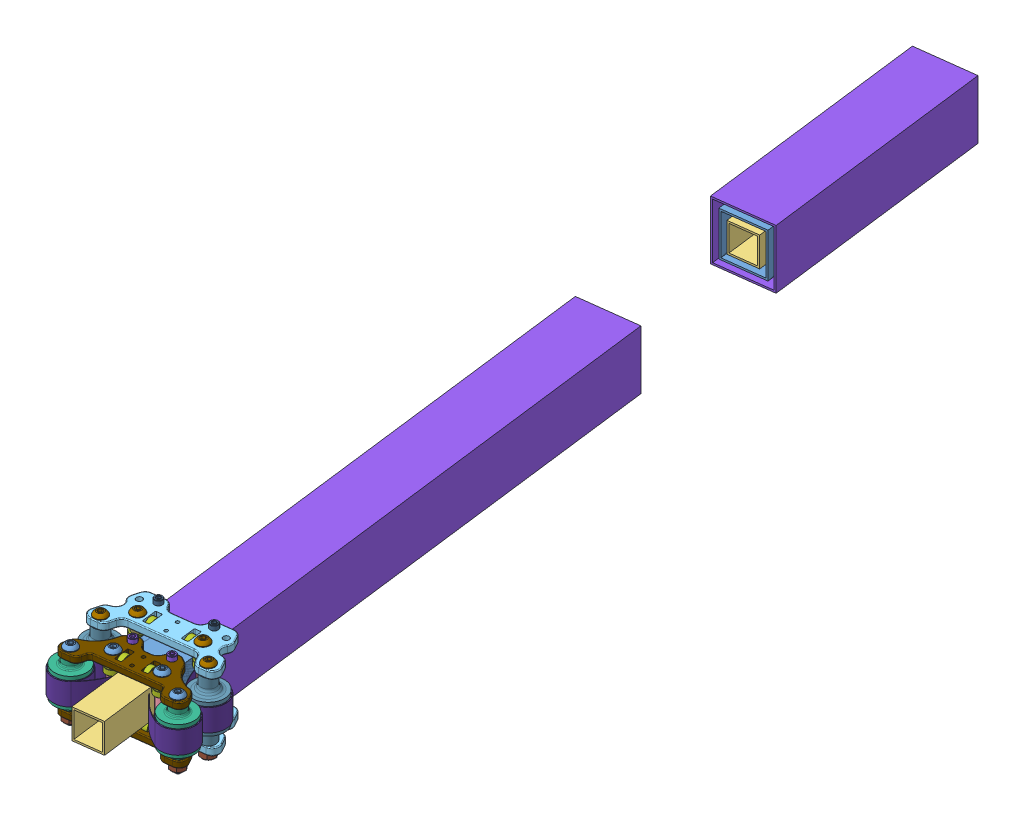
SolidWorks assembly telescoping arm, configuration Default. Lengths in mm.
Overall size (219.65 74.15 857.68).
95 component instances, 28 part files, 0 mates.
Components (placement in the parent):
- 2 x 2 Inch Stage.stp-1: 2 x 2 Inch Stage.stp [Default] at (1113.4745 353.0023 985.2524) size (183.93 74.15 806.3)
  - 1.5_inch_stage.stp-1: 1.5_inch_stage.stp [Default] at (-107.3783 0 -858.4701) size (133.34 47.37 731.79)
    - 1.5x1.5 bar.stp-1: 1.5x1.5 bar.stp [Default] at (575.8182 404.7167 1377.5179) x (-0.992268 0 0.124114) z (-0.124114 0 -0.992268) size (38.1 38.1 711.2)
    - 2x2StageInternalEndBlock.stp-1: 2x2StageInternalEndBlock.stp [Default] at (413.7616 573.8056 681.0462) x (-0.992268 0 0.124114) z (-0.124114 0 -0.992268) size (47.37 47.37 40.64)
    - 94615A115_Brass Flanged Screw-to-Expand Inserts (1).stp-1: 94615A115_Brass Flanged Screw-to-Expand Inserts (1).stp [Default] at (431.7042 573.8056 688.4011) x (0.114575 0.384452 0.916007) z (-0.047716 0.923145 -0.381479) size (7.92 9.53 7.92)
    - 97763A231_18-8 Stainless Steel Button Head Hex Drive Screws.stp-1: 97763A231_18-8 Stainless Steel Button Head Hex Drive Screws.stp [Default] at (398.9269 573.8691 692.501) x (0.124114 0.000773 0.992268) z (-0.992268 0 0.124114) size (9.17 9.17 12.09)
  - 2x2ClimberPlateAssemblyNew.stp-1: 2x2ClimberPlateAssemblyNew.stp [Default] at (310.1471 56.4224 225.65) x (0.992268 0 -0.124114) z (0.124114 0 0.992268) size (102.18 13.04 44.45)
    - 2x2NewClimberPlateConcept.stp-1: 2x2NewClimberPlateConcept.stp [Default] at (71.6924 542.7705 -285.0056) x (-1 0 0) z (0 1 0) size (102.18 44.45 8.76)
    - 98381A545_ALLOY STEEL DOWEL PIN.stp-1: 98381A545_ALLOY STEEL DOWEL PIN.stp [Default] at (46.4194 542.6435 281.8589) x (-1 0 0) z (0 -0.467381 0.884056) size (34.92 6.35 6.35)
    - TTB-0027_.50OD_.25ID_.188WD.stp-1: TTB-0027_.50OD_.25ID_.188WD.stp [Default] at (31.3382 542.6435 281.8589) x (0 0.013886 0.999904) z (-1 0 0) size (12.7 12.7 4.76)
    - TTB-0027_.50OD_.25ID_.188WD.stp-2: TTB-0027_.50OD_.25ID_.188WD.stp [Default] at (61.5007 542.6435 281.8589) x (0 0.005291 0.999986) z (-1 0 0) size (12.7 12.7 4.76)
  - 2x2ClimberPlateAssemblyNew.stp-2: 2x2ClimberPlateAssemblyNew.stp [Default] at (402.0161 1091.1635 214.1589) x (-0.992268 0 0.124114) z (0.124114 0 0.992268) size (102.18 13.04 44.45)
    - 2x2NewClimberPlateConcept.stp-1: 2x2NewClimberPlateConcept.stp [Default] at (71.6924 542.7705 -285.0056) x (-1 0 0) z (0 1 0) size (102.18 44.45 8.76)
    - 98381A545_ALLOY STEEL DOWEL PIN.stp-1: 98381A545_ALLOY STEEL DOWEL PIN.stp [Default] at (46.4194 542.6435 281.8589) x (-1 0 0) z (0 -0.467381 0.884056) size (34.92 6.35 6.35)
    - TTB-0027_.50OD_.25ID_.188WD.stp-1: TTB-0027_.50OD_.25ID_.188WD.stp [Default] at (31.3382 542.6435 281.8589) x (0 0.013886 0.999904) z (-1 0 0) size (12.7 12.7 4.76)
    - TTB-0027_.50OD_.25ID_.188WD.stp-2: TTB-0027_.50OD_.25ID_.188WD.stp [Default] at (61.5007 542.6435 281.8589) x (0 0.005291 0.999986) z (-1 0 0) size (12.7 12.7 4.76)
  - 2x2 Box.stp-1: 2x2 Box.stp [Default] at (320.6921 548.3929 -267.6788) x (-0.992268 0 0.124114) z (0.124114 0 0.992268) size (50.8 50.8 762)
  - 91255A529_NO THREADS_Button Head Hex Drive Screw (1).stp-1: 91255A529_NO THREADS_Button Head Hex Drive Screw (1).stp [Default] at (366.1553 609.0227 504.1716) x (0.396837 0 -0.917889) z (0 1 0) size (11.1 11.1 73.2)
  - 90044A515_Black-Oxide Alloy Steel Socket Head Screw.stp-1: 90044A515_Black-Oxide Alloy Steel Socket Head Screw.stp [Default] at (410.673 605.6699 482.6046) x (0.993633 0 -0.112668) z (0 1 0) size (6.86 6.86 74.15)
  - 90044A515_Black-Oxide Alloy Steel Socket Head Screw.stp-2: 90044A515_Black-Oxide Alloy Steel Socket Head Screw.stp [Default] at (367.8773 605.6699 487.9575) x (0.430705 0 0.902493) z (0 1 0) size (6.86 6.86 74.15)
  - 91255A529_NO THREADS_Button Head Hex Drive Screw (1).stp-2: 91255A529_NO THREADS_Button Head Hex Drive Screw (1).stp [Default] at (351.7432 609.0227 521.973) x (-0.099638 0 0.995024) z (0 1 0) size (11.1 11.1 73.2)
  - 91255A529_NO THREADS_Button Head Hex Drive Screw (1).stp-3: 91255A529_NO THREADS_Button Head Hex Drive Screw (1).stp [Default] at (434.6883 609.0227 511.5981) x (1 0 0) z (0 1 0) size (11.1 11.1 73.2)
  - 91255A529_NO THREADS_Button Head Hex Drive Screw (1).stp-4: 91255A529_NO THREADS_Button Head Hex Drive Screw (1).stp [Default] at (416.3356 609.0227 497.895) x (0.998718 0 -0.050617) z (0 1 0) size (11.1 11.1 73.2)
  - TTB-0027_.50OD_.25ID_.188WD.stp-1: TTB-0027_.50OD_.25ID_.188WD.stp [Default] at (416.3356 557.2004 497.895) x (-0.032207 0 0.999481) z (0 1 0) size (12.7 12.7 4.76)
  - TTB-0027_.50OD_.25ID_.188WD.stp-2: TTB-0027_.50OD_.25ID_.188WD.stp [Default] at (416.3356 590.4617 497.895) x (-0.065423 0 0.997858) z (0 1 0) size (12.7 12.7 4.76)
  - TTB-0027_.50OD_.25ID_.188WD.stp-3: TTB-0027_.50OD_.25ID_.188WD.stp [Default] at (366.1553 557.2004 504.1716) x (-0.065423 0 0.997858) z (0 1 0) size (12.7 12.7 4.76)
  - TTB-0027_.50OD_.25ID_.188WD.stp-4: TTB-0027_.50OD_.25ID_.188WD.stp [Default] at (366.1553 590.4617 504.1716) x (-0.065423 0 0.997858) z (0 1 0) size (12.7 12.7 4.76)
  - 90101A230_18-8 Stainless Steel Thin Nylon-Insert Locknut.stp-1: 90101A230_18-8 Stainless Steel Thin Nylon-Insert Locknut.stp [Default] at (434.6883 541.9159 511.5981) x (0.797272 0 -0.60362) z (-0.60362 0 -0.797272) size (11.11 5.2 12.83)
  - 90101A230_18-8 Stainless Steel Thin Nylon-Insert Locknut.stp-2: 90101A230_18-8 Stainless Steel Thin Nylon-Insert Locknut.stp [Default] at (416.3356 541.9159 497.895) x (0.921386 0 0.388648) z (0.388648 0 -0.921386) size (11.11 5.2 12.83)
  - 90101A230_18-8 Stainless Steel Thin Nylon-Insert Locknut.stp-3: 90101A230_18-8 Stainless Steel Thin Nylon-Insert Locknut.stp [Default] at (351.7432 541.9159 521.973) x (0.797272 0 -0.60362) z (-0.60362 0 -0.797272) size (11.11 5.2 12.83)
  - 90101A230_18-8 Stainless Steel Thin Nylon-Insert Locknut.stp-4: 90101A230_18-8 Stainless Steel Thin Nylon-Insert Locknut.stp [Default] at (366.1553 541.9159 504.1716) x (0.797272 0 -0.60362) z (-0.60362 0 -0.797272) size (11.11 5.2 12.83)
  - QuaterInchTelescopingSpacer.stp-1: QuaterInchTelescopingSpacer.stp [Default] at (391.2422 599.1929 504.1716) x (1 0 0) z (0 -1 0) size (9.27 9.27 6.35)
  - QuaterInchTelescopingSpacer.stp-2: QuaterInchTelescopingSpacer.stp [Default] at (391.2422 554.8191 504.1844) x (1 0 0.000511) z (0 -1 0) size (9.27 9.27 6.35)
  - 1.122InchTelescopingSpacer.stp-1: 1.122InchTelescopingSpacer.stp [Default] at (391.2422 588.0804 504.1716) x (1 0 0) z (0 -1 0) size (8.76 8.76 28.5)
  - QuaterInchTelescopingSpacer.stp-3: QuaterInchTelescopingSpacer.stp [Default] at (440.4399 599.1929 504.8475) x (0.96083 0 0.277139) z (0 -1 0) size (9.27 9.27 6.35)
  - QuaterInchTelescopingSpacer.stp-4: QuaterInchTelescopingSpacer.stp [Default] at (409.5553 554.8191 522.0482) x (-0.270275 0 0.962783) z (0 -1 0) size (9.27 9.27 6.35)
  - 94615A115_Brass Flanged Screw-to-Expand Inserts (1).stp-1: 94615A115_Brass Flanged Screw-to-Expand Inserts (1).stp [Default] at (290.8052 573.8056 -165.8762) x (0.123955 0.050546 0.991) z (0.006274 -0.998722 0.050156) size (7.92 9.53 7.92)
  - 97763A231_18-8 Stainless Steel Button Head Hex Drive Screws.stp-1: 97763A231_18-8 Stainless Steel Button Head Hex Drive Screws.stp [Default] at (323.7085 573.8691 -169.9917) x (-0.124114 0 -0.992268) z (0.992268 0 -0.124114) size (9.17 9.17 12.09)
  - 1.122InchTelescopingSpacer.stp-2: 1.122InchTelescopingSpacer.stp [Default] at (441.4226 588.0804 497.895) x (1 0 0) z (0 -1 0) size (8.76 8.76 28.5)
  - 1InchCFSpringRetentionSpacer_BaseStage.stp-1: 1InchCFSpringRetentionSpacer_BaseStage.stp [Default] at (351.7432 564.2679 521.973) x (1 0 0) z (0 -1 0) size (27.94 27.94 15.88)
  - 1InchCFSpringRetentionSpacer_BaseStage.stp-2: 1InchCFSpringRetentionSpacer_BaseStage.stp [Default] at (434.6883 583.3179 511.5981) x (-0.043542 0 0.999052) z (0 1 0) size (27.94 27.94 15.88)
  - 1InchCFSpringRetentionSpacer_BaseStage.stp-3: 1InchCFSpringRetentionSpacer_BaseStage.stp [Default] at (351.7432 583.3179 521.973) x (1 0 0) z (0 1 0) size (27.94 27.94 15.88)
  - 1InchCFSpringRetentionSpacer_BaseStage.stp-4: 1InchCFSpringRetentionSpacer_BaseStage.stp [Default] at (434.6883 564.2679 511.5981) x (0.999991 0 -0.00417) z (0 -1 0) size (27.94 27.94 15.88)
  - 90101A009_18-8 Stainless Steel Thin Nylon-Insert Locknut (1).stp-1: 90101A009_18-8 Stainless Steel Thin Nylon-Insert Locknut (1).stp [Default] at (368.252 541.9159 487.9106) x (0.797272 0 -0.60362) z (-0.60362 0 -0.797272) size (8.73 4.37 10.08)
  - 9293K56_SpringRoller.stp-1: 9293K56_SpringRoller.stp [Default] at (351.7432 564.2679 521.973) x (0.41705 0 -0.908884) z (0 1 0) size (20.07 20.07 19.05)
  - 9293K56_SpringRoller.stp-2: 9293K56_SpringRoller.stp [Default] at (434.6883 583.3179 511.5981) x (0.41705 0 0.908884) z (0 -1 0) size (20.07 20.07 19.05)
  - 9293K56_Constant-Force Spring.stp-1: 9293K56_Constant-Force Spring.stp [Default] at (434.7326 573.7929 511.5599) x (0 -1 0) z (-0.934501 0 0.355959) size (19.06 41.04 33.21)
  - 9293K56_Constant-Force Spring.stp-2: 9293K56_Constant-Force Spring.stp [Default] at (351.6902 573.7929 521.9484) x (0 1 0) z (0.996341 0 0.085466) size (19.06 41.04 33.21)
  - 90101A009_18-8 Stainless Steel Thin Nylon-Insert Locknut (1).stp-2: 90101A009_18-8 Stainless Steel Thin Nylon-Insert Locknut (1).stp [Default] at (410.673 541.9159 482.6046) x (0.797272 0 -0.60362) z (-0.60362 0 -0.797272) size (8.73 4.37 10.08)
- Stage 2 BOM - 1.5 inch to 1 inch Kit.stp-1: Stage 2 BOM - 1.5 inch to 1 inch Kit.stp [Default] at (1071.3002 772.575 539.439) x (0.992268 0 -0.124114) z (0.124114 0 0.992268) size (125.22 66.32 768.66)
  - 1.5ClimberPlateNewDesign.stp-1: 1.5ClimberPlateNewDesign.stp [Default] at (293.5653 129.5314 1017.7273) x (1 0 0) z (0 1 0) size (98.65 41.27 8)
  - 1.5ClimberPlateNewDesign.stp-2: 1.5ClimberPlateNewDesign.stp [Default] at (331.6653 179.0614 1017.7273) x (-1 0 0) z (0 -1 0) size (98.65 41.27 8)
  - 91255A528_NO THREADS_Button Head Hex Drive Screw.stp-1: 91255A528_NO THREADS_Button Head Hex Drive Screw.stp [Default] at (354.2078 182.4142 1039.3173) x (0.997583 0 0.069478) z (0 1 0) size (11.1 11.1 60.5)
  - 91255A528_NO THREADS_Button Head Hex Drive Screw.stp-2: 91255A528_NO THREADS_Button Head Hex Drive Screw.stp [Default] at (331.551 182.4142 1025.9823) x (1 0 0.000115) z (0 1 0) size (11.1 11.1 60.5)
  - 91255A528_NO THREADS_Button Head Hex Drive Screw.stp-3: 91255A528_NO THREADS_Button Head Hex Drive Screw.stp [Default] at (293.6796 182.4142 1025.9823) x (0.942114 0 0.335293) z (0 1 0) size (11.1 11.1 60.5)
  - 91255A528_NO THREADS_Button Head Hex Drive Screw.stp-4: 91255A528_NO THREADS_Button Head Hex Drive Screw.stp [Default] at (271.0228 182.4142 1039.3173) x (1 0 0) z (0 1 0) size (11.1 11.1 60.5)
  - 98381A542_ALLOY STEEL DOWEL PIN.stp-1: 98381A542_ALLOY STEEL DOWEL PIN.stp [Default] at (312.5899 173.2194 1025.9545) x (1 0 0) z (0 -0.047568 0.998868) size (25.4 6.35 6.35)
  - 98381A542_ALLOY STEEL DOWEL PIN.stp-2: 98381A542_ALLOY STEEL DOWEL PIN.stp [Default] at (312.5899 135.3734 1025.9545) x (1 0 0) z (0 -0.129807 0.991539) size (25.4 6.35 6.35)
  - TTB-0027_.50OD_.25ID_.188WD.stp-1: TTB-0027_.50OD_.25ID_.188WD.stp [Default] at (322.7054 135.3734 1025.9545) x (0 -0.059569 0.998224) z (-1 0 0) size (12.7 12.7 4.76)
  - TTB-0027_.50OD_.25ID_.188WD.stp-2: TTB-0027_.50OD_.25ID_.188WD.stp [Default] at (302.4743 135.3734 1025.9545) x (0 0.249065 0.968487) z (-1 0 0) size (12.7 12.7 4.76)
  - TTB-0027_.50OD_.25ID_.188WD.stp-3: TTB-0027_.50OD_.25ID_.188WD.stp [Default] at (293.6796 166.19 1025.9823) x (-0.99026 0 0.139228) z (0 1 0) size (12.7 12.7 4.76)
  - TTB-0027_.50OD_.25ID_.188WD.stp-4: TTB-0027_.50OD_.25ID_.188WD.stp [Default] at (293.6796 142.2505 1025.9823) x (1 0 0) z (0 1 0) size (12.7 12.7 4.76)
  - TTB-0027_.50OD_.25ID_.188WD.stp-5: TTB-0027_.50OD_.25ID_.188WD.stp [Default] at (331.551 166.19 1025.9823) x (-0.070413 0 0.997518) z (0 1 0) size (12.7 12.7 4.76)
  - TTB-0027_.50OD_.25ID_.188WD.stp-6: TTB-0027_.50OD_.25ID_.188WD.stp [Default] at (302.4743 173.2194 1025.9545) x (0 -0.065423 0.997858) z (-1 0 0) size (12.7 12.7 4.76)
  - TTB-0027_.50OD_.25ID_.188WD.stp-7: TTB-0027_.50OD_.25ID_.188WD.stp [Default] at (322.7054 173.2194 1025.9545) x (0 0.136778 0.990602) z (-1 0 0) size (12.7 12.7 4.76)
  - TTB-0027_.50OD_.25ID_.188WD.stp-8: TTB-0027_.50OD_.25ID_.188WD.stp [Default] at (331.551 142.2505 1025.9823) x (1 0 0) z (0 1 0) size (12.7 12.7 4.76)
  - 1x1.stp-1: 1x1.stp [Default] at (299.8518 166.9329 770.3868) x (0 -1 0) z (-1 0 0) size (25.4 711.2 25.4)
  - 90101A230_18-8 Stainless Steel Thin Nylon-Insert Locknut.stp-1: 90101A230_18-8 Stainless Steel Thin Nylon-Insert Locknut.stp [Default] at (293.6796 129.5314 1025.9823) x (0.866025 0 -0.5) z (-0.5 0 -0.866025) size (11.11 5.2 12.83)
  - 90101A230_18-8 Stainless Steel Thin Nylon-Insert Locknut.stp-2: 90101A230_18-8 Stainless Steel Thin Nylon-Insert Locknut.stp [Default] at (354.2078 129.5314 1039.3173) x (-0.866025 0 -0.5) z (-0.5 0 0.866025) size (11.11 5.2 12.83)
  - 90101A230_18-8 Stainless Steel Thin Nylon-Insert Locknut.stp-3: 90101A230_18-8 Stainless Steel Thin Nylon-Insert Locknut.stp [Default] at (331.551 129.5314 1025.9823) x (0.866025 0 0.5) z (0.5 0 -0.866025) size (11.11 5.2 12.83)
  - 90101A230_18-8 Stainless Steel Thin Nylon-Insert Locknut.stp-4: 90101A230_18-8 Stainless Steel Thin Nylon-Insert Locknut.stp [Default] at (271.0228 129.5314 1039.3173) x (0.866025 0 0.5) z (0.5 0 -0.866025) size (11.11 5.2 12.83)
  - .607TelescopingSpacer.stp-1: .607TelescopingSpacer.stp [Default] at (354.9872 144.6317 1017.0327) x (0.934202 0 -0.356745) z (0 1 0) size (9.02 9.02 19.18)
  - .607TelescopingSpacer.stp-2: .607TelescopingSpacer.stp [Default] at (318.7665 144.6317 1026.006) x (1 0 0.000943) z (0 1 0) size (9.02 9.02 19.18)
  - .188TelescopingSpacer.stp-1: .188TelescopingSpacer.stp [Default] at (356.6379 173.3464 1025.9823) x (1 0 0) z (0 -1 0) size (8.81 8.81 4.78)
  - .188TelescopingSpacer.stp-2: .188TelescopingSpacer.stp [Default] at (318.7665 173.3464 1025.9823) x (1 0 0) z (0 -1 0) size (8.81 8.81 4.78)
  - .188TelescopingSpacer.stp-3: .188TelescopingSpacer.stp [Default] at (282.8338 139.8692 1048.6036) x (-0.432328 0 0.901716) z (0 -1 0) size (8.81 8.81 4.78)
  - .188TelescopingSpacer.stp-4: .188TelescopingSpacer.stp [Default] at (326.9008 139.8692 1001.3302) x (-0.18536 0 -0.982671) z (0 -1 0) size (8.81 8.81 4.78)
  - 9293K56_Constant-Force Spring.stp-1: 9293K56_Constant-Force Spring.stp [Default] at (354.2389 154.2964 1039.2678) x (0 -1 0) z (-0.788944 0 0.614465) size (19.06 41.04 33.21)
  - 1InchCFSpringRetentionSpacer.stp-1: 1InchCFSpringRetentionSpacer.stp [Default] at (271.0228 144.7714 1039.3173) x (0.41705 0 0.908884) z (0 -1 0) size (27.94 27.94 9.53)
  - 1InchCFSpringRetentionSpacer.stp-2: 1InchCFSpringRetentionSpacer.stp [Default] at (354.2078 144.7714 1039.3173) x (0.383782 0 0.923424) z (0 -1 0) size (27.94 27.94 9.53)
  - 1InchCFSpringRetentionSpacer.stp-3: 1InchCFSpringRetentionSpacer.stp [Default] at (354.2078 163.8214 1039.3173) x (0.830028 0 -0.557722) z (0 1 0) size (27.94 27.94 9.53)
  - 1InchCFSpringRetentionSpacer.stp-4: 1InchCFSpringRetentionSpacer.stp [Default] at (271.0228 163.8214 1039.3173) x (0.383782 0 -0.923424) z (0 1 0) size (27.94 27.94 9.53)
  - 9293K56_Constant-Force Spring.stp-2: 9293K56_Constant-Force Spring.stp [Default] at (270.9861 154.2964 1039.2718) x (0 1 0) z (0.855643 0 0.517566) size (19.06 41.04 33.21)
  - 9293K56_SpringRoller.stp-1: 9293K56_SpringRoller.stp [Default] at (271.0228 163.8214 1039.3173) x (0.416799 0 0.908999) z (0 -1 0) size (20.07 20.07 19.05)
  - 1x1StageInternalEndBlock.stp-1: 1x1StageInternalEndBlock.stp [Default] at (312.6153 154.2964 363.9868) x (-1 0 0) z (0 0 -1) size (34.67 34.67 40)
  - 90101A009_18-8 Stainless Steel Thin Nylon-Insert Locknut (1).stp-1: 90101A009_18-8 Stainless Steel Thin Nylon-Insert Locknut (1).stp [Default] at (327.8299 129.5314 1011.3773) x (0.866025 0 0.5) z (0.5 0 -0.866025) size (8.73 4.37 10.08)
  - 90101A009_18-8 Stainless Steel Thin Nylon-Insert Locknut (1).stp-2: 90101A009_18-8 Stainless Steel Thin Nylon-Insert Locknut (1).stp [Default] at (297.4007 129.5314 1011.3773) x (-0.866025 0 -0.5) z (-0.5 0 0.866025) size (8.73 4.37 10.08)
  - 90044A513_Black-Oxide Alloy Steel Socket Head Screw.stp-1: 90044A513_Black-Oxide Alloy Steel Socket Head Screw.stp [Default] at (297.4007 179.0614 1011.3773) x (0.353324 0 0.935501) z (0 1 0) size (10.11 10 66.32)
  - 90044A513_Black-Oxide Alloy Steel Socket Head Screw.stp-2: 90044A513_Black-Oxide Alloy Steel Socket Head Screw.stp [Default] at (327.8299 179.0614 1011.3773) x (1 0 0) z (0 1 0) size (10.11 10 66.32)
  - 94615A212_Brass Flanged Screw-to-Expand Inserts (1).stp-1: 94615A212_Brass Flanged Screw-to-Expand Inserts (1).stp [Default] at (301.9473 154.2964 373.5118) x (0 -0.59679 -0.802398) z (0 0.802398 -0.59679) size (7.14 7.14 7.14)
  - 94615A212_Brass Flanged Screw-to-Expand Inserts (1).stp-2: 94615A212_Brass Flanged Screw-to-Expand Inserts (1).stp [Default] at (323.2833 154.2964 373.5118) x (0 0.670342 -0.742052) z (0 -0.742052 -0.670342) size (7.14 7.14 7.14)
  - 97763A504_18-8 Stainless Steel Button Head Hex Drive Screws.stp-1: 97763A504_18-8 Stainless Steel Button Head Hex Drive Screws.stp [Default] at (302.0806 154.2964 373.5118) x (0 0 1) z (-1 0 0) size (7.92 7.92 10.15)
  - 97763A504_18-8 Stainless Steel Button Head Hex Drive Screws.stp-2: 97763A504_18-8 Stainless Steel Button Head Hex Drive Screws.stp [Default] at (323.0229 154.2964 373.5118) x (0 0 -1) z (1 0 0) size (7.92 7.92 10.15)
  - 1.5x1.5 bar.stp-1: 1.5x1.5 bar.stp [Default] at (386.9135 -14.856 1017.7273) x (-1 0 0) z (0 0 -1) size (38.1 38.1 711.2)
  - 9293K56_SpringRoller.stp-2: 9293K56_SpringRoller.stp [Default] at (354.2078 163.8214 1039.3173) x (0.416799 0 0.908999) z (0 -1 0) size (20.07 20.07 19.05)
